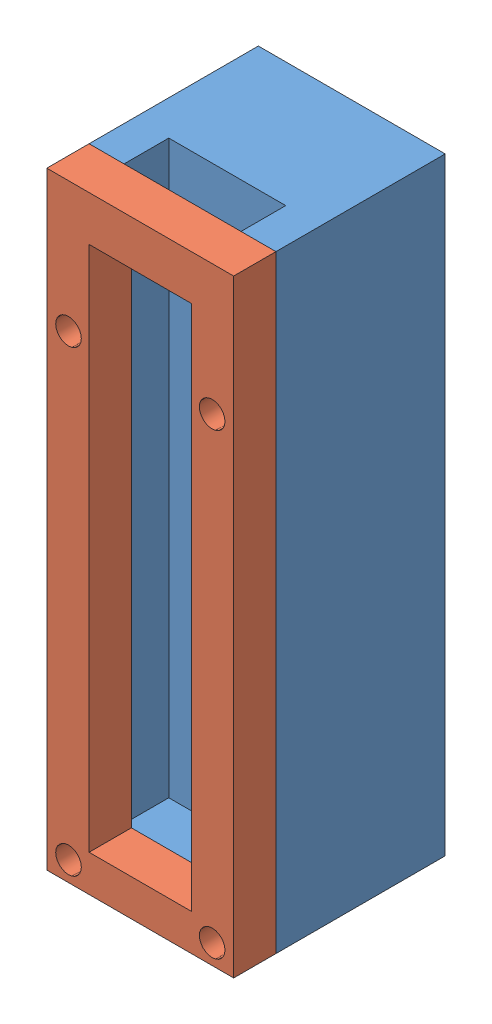
SolidWorks assembly PMD heat sink complete, configuration Default. Lengths in mm.
Overall size (29.16 94.86 33.01).
2 component instances, 2 part files, 3 mates.
Components (placement in the parent):
- PMD camera holder heat sink-1: PMD camera holder heat sink [Default] at (-11.2109 -38.2595 99.4357) size (29.16 94.86 26.41)
- PMD heat sink front face-1: PMD heat sink front face [Default] at (3.3691 -11.6195 134.0057) size (29.16 94.86 6.69)
Mates (geometry in assembly coordinates):
- Coincident1: coincident anti-aligned: plane of PMD camera holder heat sink-1 through (-11.2109 -38.2595 134.0057) normal (0 0 1); plane of PMD heat sink front face-1 through (3.3691 -11.6195 134.0057) normal (0 0 -1)
- Coincident2: coincident aligned: plane of PMD camera holder heat sink-1 through (3.3691 36.7405 135.5057) normal (1 0 0); plane of PMD heat sink front face-1 through (3.3691 -11.6195 140.6057) normal (1 0 0)
- Coincident3: coincident aligned: plane of PMD camera holder heat sink-1 through (-11.2109 83.2405 99.4357) normal (0 1 0); plane of PMD heat sink front face-1 through (-19.1909 83.2405 140.6057) normal (0 1 0)
